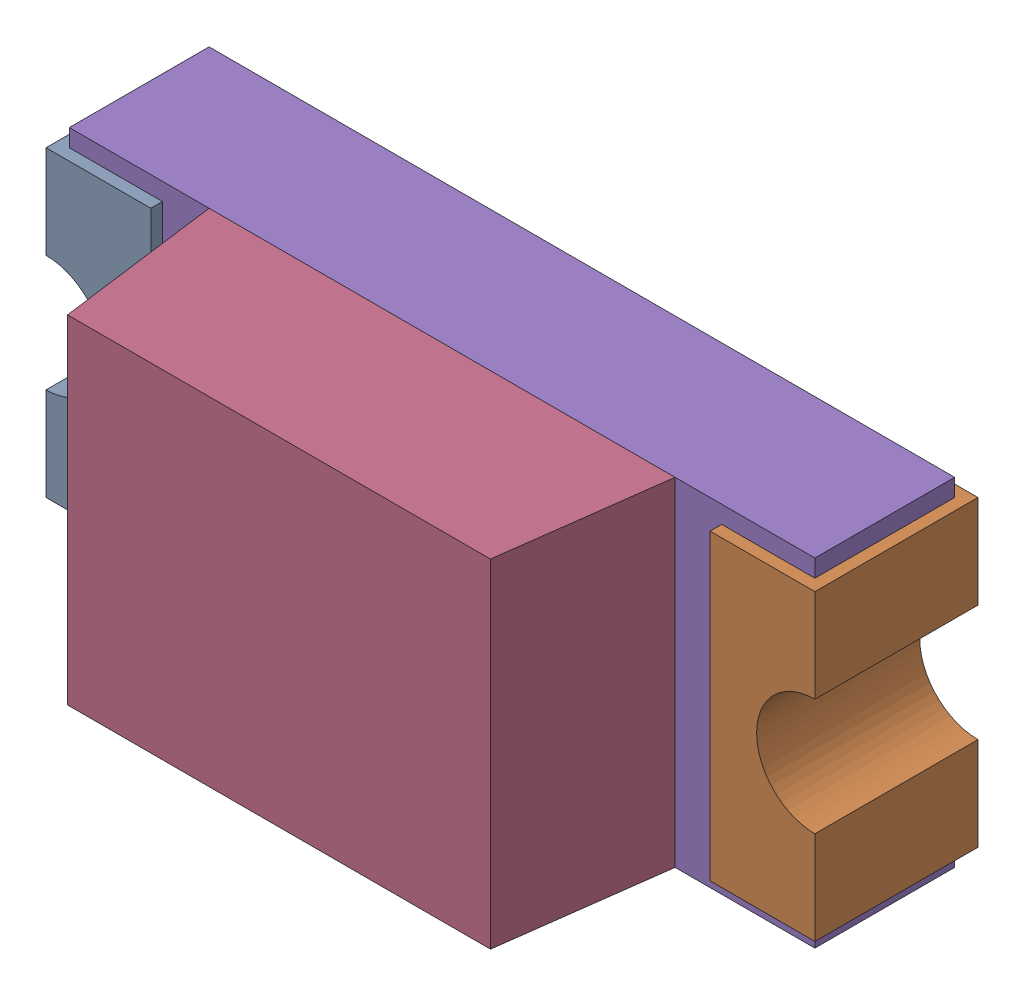
SolidWorks assembly P1, configuration Standard. Lengths in mm.
Overall size (1.65 0.73 0.68).
6 component instances, 5 part files, 0 mates.
Components (placement in the parent):
- P1-subassembly-1-1: P1-subassembly-1 [Standard] at (14.7501 -5.4999 0) x (0 1 0) z (0 0 1) size (0.72 1.65 0.68)
  - User Library-LED SMD0603-1: User Library-LED SMD0603 [Standard] at origin size (0.65 0.28 0.35)
  - User Library-LED SMD0603-1-1: User Library-LED SMD0603-1 [Standard] at origin size (0.65 0.28 0.35)
  - User Library-LED SMD0603-2-1: User Library-LED SMD0603-2 [Standard] at origin size (0.15 0.16 0.07)
  - User Library-LED SMD0603-3-1: User Library-LED SMD0603-3 [Standard] at origin size (0.72 1 0.35)
  - User Library-LED SMD0603-4-1: User Library-LED SMD0603-4 [Standard] at origin size (0.72 1.6 0.3)
